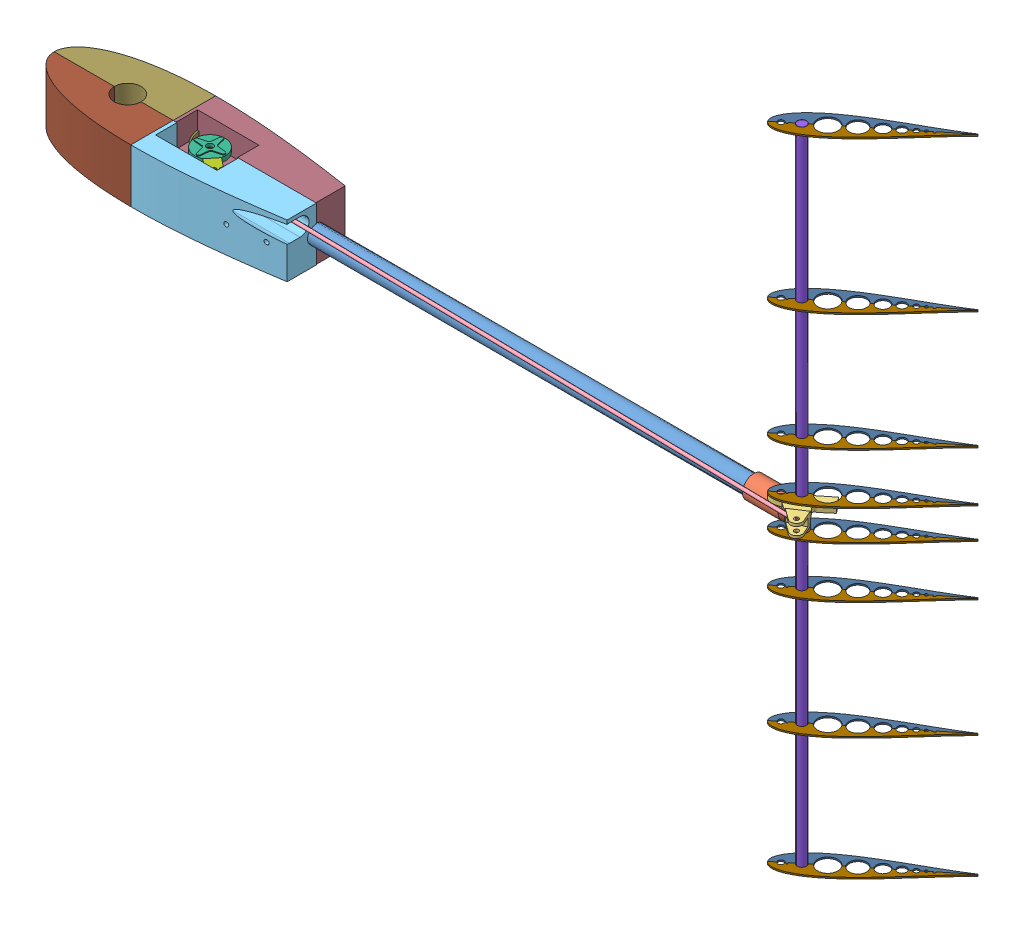
SolidWorks assembly Trim Tab, configuration Default. Lengths in mm.
Overall size (1215.91 916.52 208.54).
36 component instances, 13 part files, 53 mates.
Components (placement in the parent):
- Trim Tab Connector rod-1: Trim Tab Connector rod [Default] at (172.7333 -40.1622 -0.3772) x (0 -0.785901 0.618352) z (1 0 0) size (25.4 25.4 774.7)
- Tab mast connector-1: Tab mast connector [Default] at (965.2133 -40.1622 -0.3772) x (-1 0 0) z (0 0 -1) size (77.47 35.56 32.36)
- Push Pull Rod Connector Left Side-1: Push Pull Rod Connector Left Side [Default] at (959.2348 -14.6987 17.4744) x (0.77872 0 -0.627372) z (0 -1 0) size (118.86 59.06 18.8)
- Rod-1: Rod [Default] at (153.6428 -12.3492 25.2502) x (0.016515 0 -0.999864) z (0.999864 0 0.016515) size (4.83 4.83 847.09)
- H1S2-1: H1S2 [Default] at (-98.9704 -2.7675 0) x (1 0 0) z (0 1 0) size (277.53 60.37 76.2)
- Servo Cap-1: Servo Cap [Default] at (78.7197 -18.6927 -77.0317) x (-0.082926 0 -0.996556) z (0.996556 0 -0.082926) size (61.69 13.97 62.71)
  - Servo Cap Lower Half-1: Servo Cap Lower Half [Default] at (-80.0498 3.6288 37.6188) size (43.18 7.62 43.18)
  - servo arm-1: servo arm [Default] at (-80.0498 -2.7212 37.6188) x (-0.693059 0 0.720881) z (-0.720881 0 -0.693059) size (56.49 13.97 20.96)
- Trim tab mast-1: Trim tab mast [Default] at (965.2133 -15.6089 -0.3772) x (-0.588378 0 -0.808586) z (0.808586 0 -0.588378) size (12.7 914.4 12.7)
- Assembly Trimtab Airfoil-1: Assembly Trimtab Airfoil [Default] at (1040.7235 16.4942 -58.8445) x (0.77872 0 -0.627372) z (0 -1 0) size (282.43 40.26 4.23)
  - Trim Tab Airfoil Full Female-1: Trim Tab Airfoil Full Female [Default] at (-297.8956 -20.5316 28.5466) size (281.79 38.82 4.23)
  - Trim Tab Airfoil Full Male-1: Trim Tab Airfoil Full Male [Default] at (-298.5353 16.6359 28.5476) size (282.43 38.64 4.23)
- Assembly Trimtab Airfoil-2: Assembly Trimtab Airfoil [Default] at (1040.7235 -27.2784 -58.8445) x (0.77872 0 -0.627372) z (0 -1 0) size (282.43 40.26 4.23)
  - Trim Tab Airfoil Full Female-1: Trim Tab Airfoil Full Female [Default] at (-297.8956 -20.5316 28.5466) size (281.79 38.82 4.23)
  - Trim Tab Airfoil Full Male-1: Trim Tab Airfoil Full Male [Default] at (-298.5353 16.6359 28.5476) size (282.43 38.64 4.23)
- Assembly Trimtab Airfoil-3: Assembly Trimtab Airfoil [Default] at (1040.7235 -440.0284 -58.8445) x (0.77872 0 -0.627372) z (0 -1 0) size (282.43 40.26 4.23)
  - Trim Tab Airfoil Full Female-1: Trim Tab Airfoil Full Female [Default] at (-297.8956 -20.5316 28.5466) size (281.79 38.82 4.23)
  - Trim Tab Airfoil Full Male-1: Trim Tab Airfoil Full Male [Default] at (-298.5353 16.6359 28.5476) size (282.43 38.64 4.23)
- Assembly Trimtab Airfoil-4: Assembly Trimtab Airfoil [Default] at (1040.7235 -99.2451 -58.8445) x (0.77872 0 -0.627372) z (0 -1 0) size (282.43 40.26 4.23)
  - Trim Tab Airfoil Full Female-1: Trim Tab Airfoil Full Female [Default] at (-297.8956 -20.5316 28.5466) size (281.79 38.82 4.23)
  - Trim Tab Airfoil Full Male-1: Trim Tab Airfoil Full Male [Default] at (-298.5353 16.6359 28.5476) size (282.43 38.64 4.23)
- Assembly Trimtab Airfoil-5: Assembly Trimtab Airfoil [Default] at (1040.7235 -266.4618 -58.8445) x (0.77872 0 -0.627372) z (0 -1 0) size (282.43 40.26 4.23)
  - Trim Tab Airfoil Full Female-1: Trim Tab Airfoil Full Female [Default] at (-297.8956 -20.5316 28.5466) size (281.79 38.82 4.23)
  - Trim Tab Airfoil Full Male-1: Trim Tab Airfoil Full Male [Default] at (-298.5353 16.6359 28.5476) size (282.43 38.64 4.23)
- Assembly Trimtab Airfoil-6: Assembly Trimtab Airfoil [Default] at (1040.7235 88.4609 -58.8445) x (0.77872 0 -0.627372) z (0 -1 0) size (282.43 40.26 4.23)
  - Trim Tab Airfoil Full Female-1: Trim Tab Airfoil Full Female [Default] at (-297.8956 -20.5316 28.5466) size (281.79 38.82 4.23)
  - Trim Tab Airfoil Full Male-1: Trim Tab Airfoil Full Male [Default] at (-298.5353 16.6359 28.5476) size (282.43 38.64 4.23)
- Assembly Trimtab Airfoil-7: Assembly Trimtab Airfoil [Default] at (1040.7235 255.6776 -58.8445) x (0.77872 0 -0.627372) z (0 -1 0) size (282.43 40.26 4.23)
  - Trim Tab Airfoil Full Female-1: Trim Tab Airfoil Full Female [Default] at (-297.8956 -20.5316 28.5466) size (281.79 38.82 4.23)
  - Trim Tab Airfoil Full Male-1: Trim Tab Airfoil Full Male [Default] at (-298.5353 16.6359 28.5476) size (282.43 38.64 4.23)
- Assembly Trimtab Airfoil-8: Assembly Trimtab Airfoil [Default] at (1040.7235 472.2549 -58.8445) x (0.77872 0 -0.627372) z (0 -1 0) size (282.43 40.26 4.23)
  - Trim Tab Airfoil Full Female-1: Trim Tab Airfoil Full Female [Default] at (-297.8956 -20.5316 28.5466) size (281.79 38.82 4.23)
  - Trim Tab Airfoil Full Male-1: Trim Tab Airfoil Full Male [Default] at (-298.5353 16.6359 28.5476) size (282.43 38.64 4.23)
- H1S1-1: H1S1 [Default] at (-99.7792 -2.7491 -0.0219) x (1 0 0) z (0 1 0) size (176.06 73.05 76.2)
- H2S1-1: H2S1 [Default] at (-98.8831 -78.2622 -0.3789) x (1 0 0) z (0 -1 0) size (176.06 60.77 76.2)
- H2S2-1: H2S2 [Default] at (-98.9704 -78.2622 -0.3772) x (1 0 0) z (0 -1 0) size (273.65 60.4 76.2)
Mates (geometry in assembly coordinates):
- Coincident1: coincident anti-aligned: plane of ? through (-97.4162 -3.3268 0) normal (0 0 -1); plane of assembly through (0 0 0) normal (0 0 1)
- Coincident3: coincident anti-aligned: axis of ? through (181.4665 -40.6991 0.0326) axis (1 0 0); axis of Trim Tab Connector rod-1 through (956.1665 -40.6991 0.0326) axis (-1 0 0)
- Coincident4: coincident anti-aligned: plane of ? through (181.4665 -40.6991 0.0326) normal (1 0 0); plane of Trim Tab Connector rod-1 through (181.4665 -40.6991 0.0326) normal (-1 0 0)
- Parallel2: parallel aligned: line of ? through (283.0665 -27.9991 0.0326) axis (0 1 0); axis of Tab mast connector-1 through (973.9465 -58.4791 0.0326) axis (0 1 0)
- Coincident8: coincident: axis of Trim Tab Connector rod-1 through (947.4333 -40.1622 -0.3772) axis (-1 0 0); axis of Tab mast connector-1 through (896.6333 -40.1622 -0.3772) axis (1 0 0)
- Coincident16: coincident: axis of Push Pull Rod Connector Left Side-1 through (997.0838 -28.7322 39.1818) axis (0 1 0); axis of Rod-1 through (997.0838 -14.7622 39.1818) axis (0 1 0)
- Coincident20: coincident anti-aligned: axis of Rod-1 through (159.6394 -19.5882 16.8837) axis (0 1 0); axis of ? through (159.6394 -14.9188 16.8837) axis (0 -1 0)
- Coincident21: coincident: axis of Trim Tab Connector rod-1 through (947.4333 -40.1622 -0.3772) axis (-1 0 0); axis of H1S2-1 through (172.7333 -40.1622 -0.3772) axis (1 0 0)
- Coincident22: coincident: plane of Trim Tab Connector rod-1 through (172.7333 -40.1622 -0.3772) normal (-1 0 0); plane of H1S2-1 through (172.7333 -40.1622 -0.3772) normal (1 0 0)
- Coincident23: coincident anti-aligned: plane of H1S2-1 through (-98.9704 -2.7675 0) normal (0 0 -1); plane of assembly through (0 0 0) normal (0 0 1)
- Distance1: distance = 6.4735 mm: plane of H1S2-1 through (75.8752 -35.3622 30.1028) normal (0 1 0); plane of ? through (122.8471 -28.8888 -0.3772) normal (0 -1 0)
- Coincident27: coincident: plane of Trim Tab Connector rod-1 through (947.4333 -40.1622 -0.3772) normal (1 0 0); plane of Tab mast connector-1 through (947.4333 -40.1622 -0.3772) normal (-1 0 0)
- Coincident28: coincident: line of ? through (122.8471 -19.3638 -0.3772) axis (0 -1 0)
- Tangent2: tangent: plane of Push Pull Rod Connector Left Side-1 through (938.0603 -9.9362 21.2526) normal (0 1 0); cylinder of Rod-1 through (1000.6173 -12.3492 39.2402) axis (-0.999864 0 -0.016515) radius 2.413
- Coincident29: coincident: line of ? through (122.8471 -7.444 -0.3772) axis (0 -1 0)
- Coincident30: coincident: axis of Rod-1 through (154.3785 -14.7622 25.2623) axis (0 1 0); axis of ? through (154.3785 -7.444 25.2623) axis (0 -1 0)
- Distance3: distance = 20.2983 mm: plane of Servo Cap-1/Servo Cap Lower Half-1 through (122.8471 -15.064 -0.3772) normal (0 -1 0); plane of H1S2-1 through (75.8752 -35.3622 30.1028) normal (0 1 0)
- Coincident38: coincident: axis of Tab mast connector-1 through (965.2133 -57.9422 -0.3772) axis (0 1 0); axis of Push Pull Rod Connector Left Side-1 through (965.2133 -22.3822 -0.3772) axis (0 1 0)
- Coincident41: coincident: plane of Tab mast connector-1 through (965.2133 -22.3822 -0.3772) normal (0 1 0); plane of Push Pull Rod Connector Left Side-1 through (959.2348 -22.3822 17.4744) normal (0 -1 0)
- Concentric1: concentric: circle of Tab mast connector-1; circle of Trim tab mast-1
- Concentric2: concentric: circle of Trim tab mast-1; circle of Assembly Trimtab Airfoil-1/Trim Tab Airfoil Full Male-1
- Coincident43: coincident: line of Push Pull Rod Connector Left Side-1 through (959.7739 -16.2862 4.005) axis (-0.77872 0 0.627372); line of Assembly Trimtab Airfoil-1/Trim Tab Airfoil Full Male-1 through (938.1813 -16.2862 21.401) axis (0.77872 0 -0.627372)
- Concentric3: concentric: circle of Trim tab mast-1; circle of Assembly Trimtab Airfoil-2/Trim Tab Airfoil Full Male-1
- Parallel3: parallel: line of Assembly Trimtab Airfoil-1/Trim Tab Airfoil Full Male-1 through (938.1813 -14.1696 21.401) axis (0.77872 0 -0.627372); line of ? through (938.1813 -57.9422 21.401) axis (0.77872 0 -0.627372)
- Coincident45: coincident: plane of Tab mast connector-1 through (965.2133 -57.9422 -0.3772) normal (0 -1 0); plane of ? through (938.1813 -57.9422 21.401) normal (0 1 0)
- Concentric6: concentric: circle of Trim tab mast-1; circle of Assembly Trimtab Airfoil-3/Trim Tab Airfoil Full Male-1
- Parallel5: parallel: line of Assembly Trimtab Airfoil-1/Trim Tab Airfoil Full Male-1 through (938.1813 -14.1696 21.401) axis (0.77872 0 -0.627372); line of ? through (938.1813 -469.2196 21.401) axis (0.77872 0 -0.627372)
- Coincident48: coincident: plane of Trim tab mast-1 through (965.2133 -469.2196 -0.3772) normal (0 -1 0); plane of Assembly Trimtab Airfoil-3/Trim Tab Airfoil Full Female-1 through (938.1813 -469.2196 21.401) normal (0 -1 0)
- Concentric7: concentric: circle of Trim tab mast-1; circle of Assembly Trimtab Airfoil-4/Trim Tab Airfoil Full Male-1
- Concentric8: concentric: circle of Trim tab mast-1; circle of Assembly Trimtab Airfoil-5/Trim Tab Airfoil Full Male-1
- Concentric9: concentric: circle of Trim tab mast-1; circle of Assembly Trimtab Airfoil-6/Trim Tab Airfoil Full Male-1
- Concentric10: concentric: circle of Trim tab mast-1; circle of Assembly Trimtab Airfoil-7/Trim Tab Airfoil Full Male-1
- Concentric12: concentric: circle of Trim tab mast-1; circle of Assembly Trimtab Airfoil-8/Trim Tab Airfoil Full Male-1
- Coincident53: coincident: plane of Trim tab mast-1 through (965.2133 445.1804 -0.3772) normal (0 1 0); plane of ? through (938.1813 445.1804 21.401) normal (0 1 0)
- Parallel9: parallel: line of ? through (938.1813 225.0138 21.401) axis (0.77872 0 -0.627372); line of ? through (938.1813 445.1804 21.401) axis (0.77872 0 -0.627372)
- Parallel10: parallel: line of ? through (938.1813 57.7971 21.401) axis (0.77872 0 -0.627372); line of ? through (938.1813 225.0138 21.401) axis (0.77872 0 -0.627372)
- Parallel13: parallel: line of ? through (938.1813 -297.1256 21.401) axis (0.77872 0 -0.627372); line of ? through (938.1813 55.6804 21.401) axis (0.77872 0 -0.627372)
- Parallel14: parallel: line of ? through (938.1813 -60.0589 21.401) axis (0.77872 0 -0.627372); line of ? through (938.1813 -297.1256 21.401) axis (0.77872 0 -0.627372)
- Parallel15: parallel: line of ? through (938.1813 -132.0256 21.401) axis (0.77872 0 -0.627372); line of ? through (938.1813 -299.2422 21.401) axis (0.77872 0 -0.627372)
- Concentric13: concentric: circle of H1S2-1; circle of H1S1-1
- Coincident54: coincident: plane of H1S2-1 through (-98.1974 -2.0622 -0.3772) normal (0 1 0); plane of H1S1-1 through (-98.8831 -2.0622 -0.3789) normal (0 1 0)
- Coincident55: coincident: plane of H1S2-1 through (70.4476 -2.7675 0) normal (-1 0 0); plane of H1S1-1 through (70.4476 -2.7491 -0.0219) normal (1 0 0)
- Concentric14: concentric: circle of H1S1-1; circle of H2S1-1
- Concentric15: concentric: circle of H1S1-1; circle of H2S1-1
- Coincident56: coincident: plane of H1S1-1 through (375.2476 23.3378 -0.3789) normal (0 0 -1); plane of H2S1-1 through (375.2476 -103.6622 -0.3789) normal (0 0 1)
- Concentric16: concentric: circle of H2S1-1; circle of H2S2-1
- Coincident59: coincident: plane of H2S1-1 through (70.4476 -78.2622 -0.3789) normal (1 0 0); plane of H2S2-1 through (70.4476 -78.2622 -0.3772) normal (-1 0 0)
- Concentric17: concentric: circle of Trim Tab Connector rod-1; circle of H2S2-1
- Distance4: distance = 69.85 mm: plane of ? through (938.1813 -14.1696 21.401) normal (0 1 0); plane of ? through (938.1813 55.6804 21.401) normal (0 -1 0)
- Distance5: distance = 69.85 mm: plane of ? through (938.1813 -60.0589 21.401) normal (0 -1 0); plane of ? through (938.1813 -129.9089 21.401) normal (0 1 0)
- Distance6: distance = 165.1 mm: plane of ? through (938.1813 57.7971 21.401) normal (0 1 0); plane of ? through (938.1813 222.8971 21.401) normal (0 -1 0)
- Distance7: distance = 165.1 mm: plane of ? through (938.1813 -132.0256 21.401) normal (0 -1 0); plane of ? through (938.1813 -297.1256 21.401) normal (0 1 0)
- Distance8: distance = 171.45 mm: plane of Assembly Trimtab Airfoil-3/Trim Tab Airfoil Full Male-1 through (938.1813 -470.6922 21.401) normal (0 1 0); plane of Assembly Trimtab Airfoil-5/Trim Tab Airfoil Full Female-1 through (938.1813 -299.2422 21.401) normal (0 -1 0)
